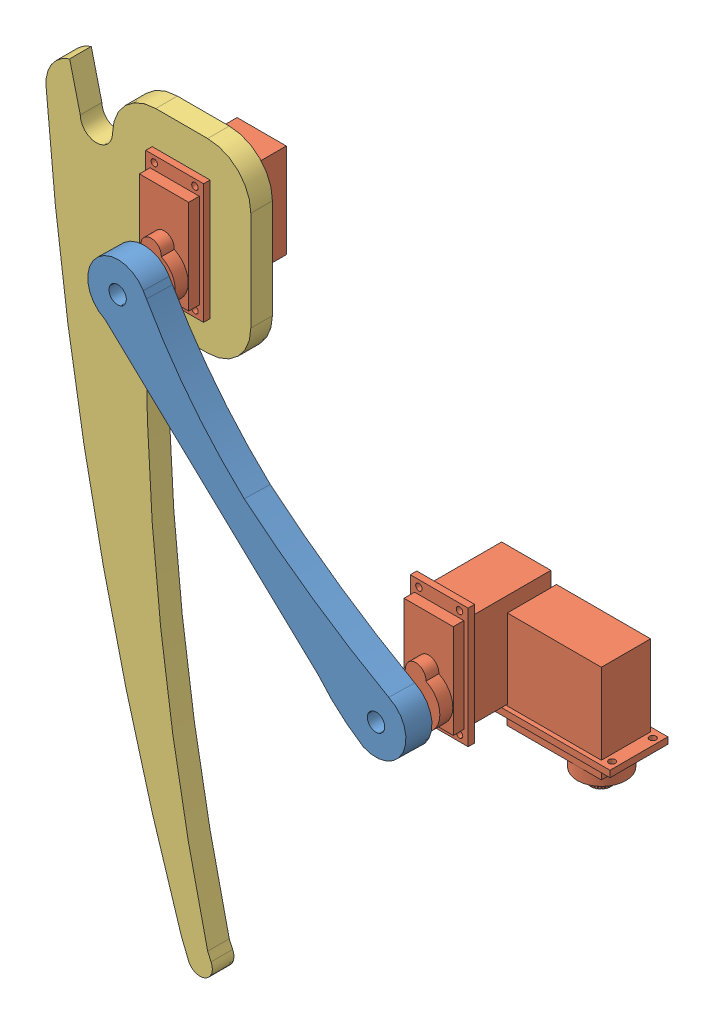
SolidWorks assembly PataComplete, configuration Default. Lengths in mm.
Overall size (122.91 168.85 37.28).
5 component instances, 3 part files, 0 mates.
Components (placement in the parent):
- Pata2-1: Pata2 [Default] at (-152.6346 -170.0138 44.9187) x (-0.912683 0.408511 -0.011306) z (0.004803 -0.01694 -0.999845) size (91.94 38.8 6)
- Servo Turningy 9g-1: Servo Turningy 9g [Valor predeterminado] at (-152.6505 -165.0366 10.1296) x (1 0 0) z (0 -1 0) size (13.4 28.6 27.8)
- Servo Turningy 9g-7: Servo Turningy 9g [Valor predeterminado] at (-213.6482 -110.33 10.3803) x (1 0 0) z (0 -1 0) size (13.4 28.6 27.8)
- Servo Turningy 9g-8: Servo Turningy 9g [Valor predeterminado] at (-136.0821 -157.6358 14.5126) x (0 0 1) z (1 0 0) size (13.4 28.6 27.8)
- Pata-3: Pata [Default] at (-207.6364 -98.5483 23.8802) x (0 1 0) z (0 0 1) size (168.85 47.43 5)
